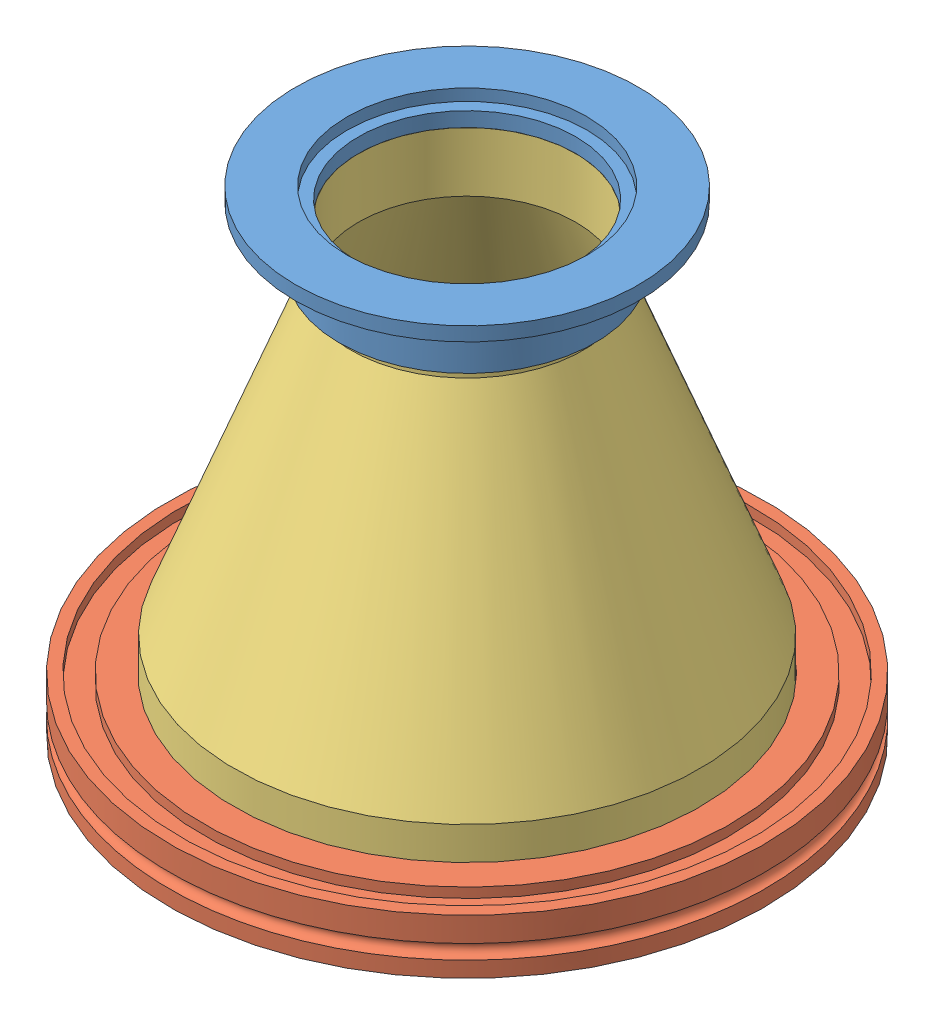
SolidWorks assembly 840020, configuration Default. Lengths in mm.
Overall size (173.93 104.01 173.93).
3 component instances, 3 part files, 4 mates.
Components (placement in the parent):
- 713004-1: 713004 [Default] at (22.9079 50.9612 57.479) size (74.93 15.75 74.93)
- 813001-1: 813001 [Default] at (22.9079 -53.0518 57.479) x (-0.898579 0 -0.438812) z (-0.438812 0 0.898579) size (130.05 11.94 130.05)
- SUB1-1: SUB1 [Default] at (22.9079 -46.7018 57.479) x (0 1 0) z (-0.869353 0 -0.494192) size (91.95 101.6 101.6)
Mates (geometry in assembly coordinates):
- Coincident1: coincident anti-aligned: plane of 713004-1 through (48.4349 45.2462 57.479) normal (0 -1 0); plane of SUB1-1 through (35.4604 45.2462 35.3974) normal (0 1 0)
- Concentric1: concentric anti-aligned: cylinder of 713004-1 through (22.9079 50.9612 57.479) axis (0 1 0) radius 27.94; cylinder of SUB1-1 through (22.9079 -46.7018 57.479) axis (0 -1 0) radius 25.4
- Coincident2: coincident anti-aligned: plane of 813001-1 through (-22.854 -46.7018 35.1316) normal (0 1 0); plane of SUB1-1 through (22.9079 -46.7018 57.479) normal (0 -1 0)
- Concentric2: concentric aligned: cylinder of 813001-1 through (22.9079 -53.0518 57.479) axis (0 -1 0) radius 50.927; cylinder of SUB1-1 through (22.9079 -46.7018 57.479) axis (0 -1 0) radius 50.8
